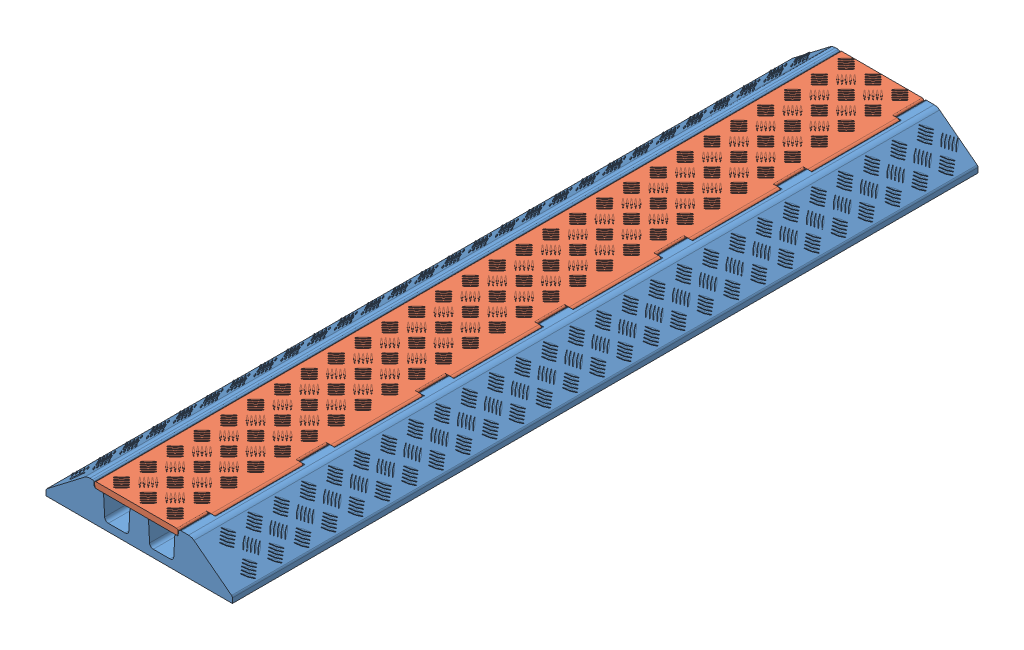
SolidWorks assembly ASY - Cable_cover, configuration По умолчанию. Lengths in mm.
Overall size (250 51 1000).
2 component instances, 2 part files, 3 mates.
Components (placement in the parent):
- Cable_cover - base-1: Cable_cover - base [По умолчанию] at origin size (250 50 1000)
- Cable_cover - cap-1: Cable_cover - cap [По умолчанию] at (-59.5313 42 0) size (120.31 9 1000)
Mates (geometry in assembly coordinates):
- Концентричный2: concentric: cylinder of Cable_cover - base-1 through (56.4687 46 300) axis (0 0 1) radius 4; cylinder of Cable_cover - cap-1 through (56.4687 46 500) axis (0 0 -1) radius 4
- Совпадение1: coincident: plane of Cable_cover - base-1 through (0 0 500) normal (0 0 1); plane of Cable_cover - cap-1 through (56.4687 46 500) normal (0 0 1)
- Граничный угол1: limit planar angle = 0 rad: plane of Cable_cover - base-1 through (-60.2645 42 -500) normal (0 1 0); plane of Cable_cover - cap-1 through (-59.5313 42 500) normal (0 -1 0)
